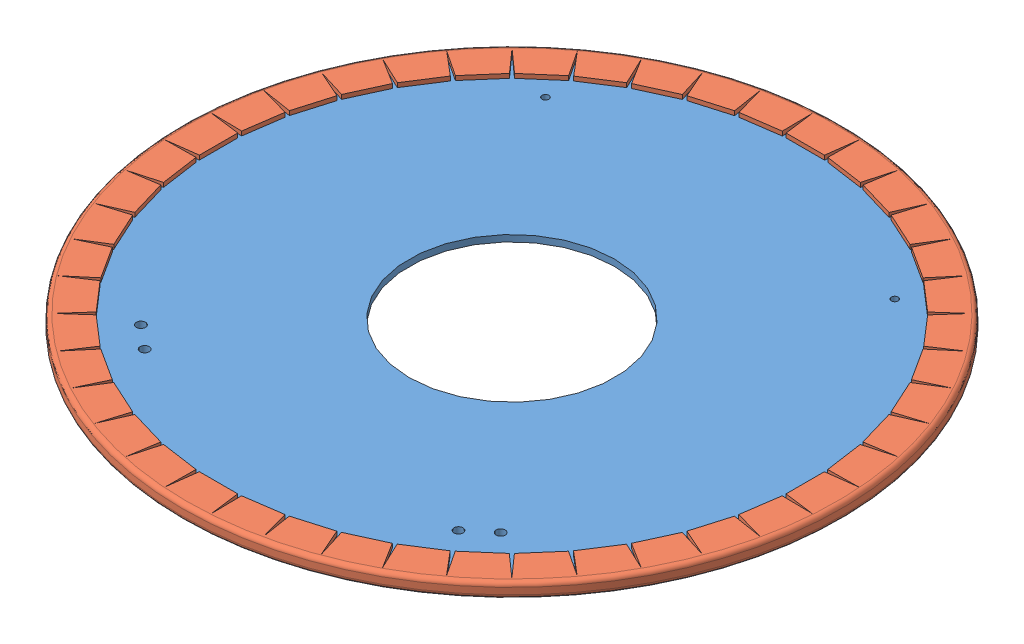
SolidWorks assembly GE-19244, configuration Sourcing. Lengths in mm.
Overall size (488.95 11.11 488.95).
20 component instances, 9 part files, 40 mates.
Components (placement in the parent):
- GE-19245-1: GE-19245 [Default] at origin size (482.6 4.76 482.6)
- GE-19153-1: GE-19153 [Default] at (0 -3.175 0) size (488.95 11.11 488.95)
- GE-19246-1: GE-19246 [1030A11] at (-132.0312 -25.527 157.0523) x (-0.642788 0 0.766044) z (0 1 0) size (50.8 38.1 25.53) (suppressed, hidden)
- GE-19246-2: GE-19246 [1030A11] at (132.0312 -25.527 157.0523) x (0.642788 0 0.766044) z (0 1 0) size (50.8 38.1 25.53) (suppressed, hidden)
- GE-19247-1: GE-19247 [Default] at (-129.594 -7.9375 -154.4441) x (0.732805 0 -0.680438) z (-0.680438 0 -0.732805) size (39.69 20.64 12.7) (suppressed, hidden)
- GE-19247-2: GE-19247 [Default] at (129.594 -7.9375 -154.4441) x (-0.777151 0 -0.629315) z (-0.629315 0 0.777151) size (39.69 20.64 12.7) (suppressed, hidden)
- spacer_.192_.5_.3125-1: spacer_.192_.5_.3125 [94639A551] at (129.594 -3.9688 -154.4441) x (1 0 0) z (0 -1 0) size (12.7 12.7 7.94) (suppressed, hidden)
- spacer_.192_.5_.3125-2: spacer_.192_.5_.3125 [94639A551] at (-129.594 -3.9688 -154.4441) x (1 0 0) z (0 -1 0) size (12.7 12.7 7.94) (suppressed, hidden)
- round_hex_.25_20_.75_full-1: round_hex_.25_20_.75_full [91255A540] at (133.4264 8.1153 141.7234) x (-0.837169 0 -0.546944) z (0 1 0) size (11.1 11.1 22.63) (suppressed, hidden)
- round_hex_.25_20_.75_full-2: round_hex_.25_20_.75_full [91255A540] at (116.4011 8.1153 156.0094) x (-0.925243 0 -0.379375) z (0 1 0) size (11.1 11.1 22.63) (suppressed, hidden)
- round_hex_.25_20_.75_full-4: round_hex_.25_20_.75_full [91255A540] at (-116.4011 8.1153 156.0094) x (-0.985271 0 -0.170998) z (0 1 0) size (11.1 11.1 22.63) (suppressed, hidden)
- round_hex_.25_20_.75_full-6: round_hex_.25_20_.75_full [91255A540] at (-133.4264 8.1153 141.7234) x (-0.997902 0 0.064746) z (0 1 0) size (11.1 11.1 22.63) (suppressed, hidden)
- nylock_.25_20-1: nylock_.25_20 [Default] at (-133.4264 -3.302 141.7234) x (-0.837169 0 -0.546944) z (-0.546944 0 0.837169) size (11.11 7.94 12.83) (suppressed, hidden)
- nylock_.25_20-2: nylock_.25_20 [Default] at (-116.4011 -3.302 156.0094) x (-0.925243 0 -0.379375) z (-0.379375 0 0.925243) size (11.11 7.94 12.83) (suppressed, hidden)
- nylock_.25_20-4: nylock_.25_20 [Default] at (116.4011 -3.302 156.0094) x (-0.985271 0 -0.170998) z (-0.170998 0 0.985271) size (11.11 7.94 12.83) (suppressed, hidden)
- nylock_.25_20-6: nylock_.25_20 [Default] at (133.4264 -3.302 141.7234) x (-0.997902 0 0.064746) z (0.064746 0 0.997902) size (11.11 7.94 12.83) (suppressed, hidden)
- round_hex_10_32_1.5_partial-1: round_hex_10_32_1.5_partial [91255A275] at (-129.594 7.3279 -154.4441) x (-0.837169 0 -0.546944) z (0 1 0) size (9.17 9.17 40.85) (suppressed, hidden)
- round_hex_10_32_1.5_partial-2: round_hex_10_32_1.5_partial [91255A275] at (129.594 7.3279 -154.4441) x (-0.837169 0 -0.546944) z (0 1 0) size (9.17 9.17 40.85) (suppressed, hidden)
- nylock_10_32-1: nylock_10_32 [90631A411] at (129.594 -23.1775 -154.4441) x (-0.837169 0 -0.546944) z (-0.546944 0 0.837169) size (9.53 5.95 11) (suppressed, hidden)
- nylock_10_32-2: nylock_10_32 [90631A411] at (-129.594 -23.1775 -154.4441) x (-0.837169 0 -0.546944) z (-0.546944 0 0.837169) size (9.53 5.95 11) (suppressed, hidden)
Mates (geometry in assembly coordinates):
- Concentric1: concentric: circle of GE-19245-1; circle of GE-19153-1
- Coincident1: coincident: plane of GE-19245-1 through (0 4.7625 0) normal (0 1 0); plane of GE-19153-1 through (0 4.7625 -190.5) normal (0 -1 0)
- Concentric2: concentric: circle of GE-19245-1; circle of GE-19246-1
- Concentric7: concentric: cylinder of GE-19245-1 through (-116.4011 0 156.0094) axis (0 -1 0) radius 3.3782; cylinder of GE-19246-1 through (-116.6929 -25.527 155.7645) axis (0 1 0) radius 3.175
- Coincident2: coincident: plane of GE-19245-1 through (0 0 0) normal (0 -1 0); plane of GE-19246-1 through (-116.1319 0 167.7408) normal (0 1 0)
- Concentric9: concentric: circle of GE-19245-1; circle of GE-19246-2
- Concentric11: concentric: cylinder of GE-19245-1 through (116.4011 0 156.0094) axis (0 -1 0) radius 3.3782; cylinder of GE-19246-2 through (116.6929 -25.527 155.7645) axis (0 1 0) radius 3.175
- Coincident4: coincident: plane of GE-19245-1 through (0 0 0) normal (0 -1 0); plane of GE-19246-2 through (145.3182 0 143.2506) normal (0 1 0)
- Concentric12: concentric: cylinder of GE-19245-1 through (129.594 0 -154.4441) axis (0 -1 0) radius 2.5527; circle of GE-19247-2
- Concentric13: concentric: circle of GE-19245-1; circle of GE-19247-1
- Coincident5: coincident: plane of assembly; plane of assembly; plane of GE-19247-1 through (-129.594 -23.1775 -154.4441) normal (0 -1 0); plane of GE-19247-2 through (129.594 -23.1775 -154.4441) normal (0 -1 0)
- Concentric14: concentric: circle of GE-19245-1; cylinder of spacer_.192_.5_.3125-1 through (129.594 -7.9375 -154.4441) axis (0 1 0) radius 2.4384
- Coincident6: coincident: plane of GE-19245-1 through (0 0 0) normal (0 -1 0); plane of spacer_.192_.5_.3125-1 through (129.594 0 -154.4441) normal (0 1 0)
- Concentric15: concentric: circle of GE-19245-1; cylinder of spacer_.192_.5_.3125-2 through (-129.594 -7.9375 -154.4441) axis (0 1 0) radius 2.4384
- Coincident7: coincident: plane of GE-19245-1 through (0 0 0) normal (0 -1 0); plane of spacer_.192_.5_.3125-2 through (-129.594 0 -154.4441) normal (0 1 0)
- Coincident8: coincident: plane of assembly; plane of assembly; plane of GE-19247-1 through (-129.594 -7.9375 -154.4441) normal (0 1 0); plane of spacer_.192_.5_.3125-2 through (-129.594 -7.9375 -154.4441) normal (0 -1 0)
- Concentric16: concentric: circle of GE-19245-1; cylinder of round_hex_.25_20_.75_full-1 through (133.4264 -14.2875 141.7234) axis (0 -1 0) radius 3.175
- Coincident9: coincident: plane of GE-19245-1 through (0 4.7625 0) normal (0 1 0); plane of round_hex_.25_20_.75_full-1 through (136.4619 4.7625 137.0772) normal (0 -1 0)
- Concentric17: concentric: cylinder of GE-19245-1 through (116.4011 0 156.0094) axis (0 -1 0) radius 3.3782; cylinder of round_hex_.25_20_.75_full-2 through (116.4011 -14.2875 156.0094) axis (0 -1 0) radius 3.175
- Coincident10: coincident: plane of GE-19245-1 through (0 4.7625 0) normal (0 1 0); plane of round_hex_.25_20_.75_full-2 through (118.5066 4.7625 150.8744) normal (0 -1 0)
- Concentric18: concentric: cylinder of GE-19245-1 through (-116.4011 0 156.0094) axis (0 -1 0) radius 3.3782; cylinder of round_hex_.25_20_.75_full-4 through (-116.4011 -14.2875 156.0094) axis (0 -1 0) radius 3.175
- Coincident11: coincident: plane of GE-19245-1 through (0 4.7625 0) normal (0 1 0); plane of round_hex_.25_20_.75_full-4 through (-115.4521 4.7625 150.5412) normal (0 -1 0)
- Concentric19: concentric: cylinder of GE-19245-1 through (-133.4264 0 141.7234) axis (0 -1 0) radius 3.3782; cylinder of round_hex_.25_20_.75_full-6 through (-133.4264 -14.2875 141.7234) axis (0 -1 0) radius 3.175
- Coincident12: coincident: plane of GE-19245-1 through (0 4.7625 0) normal (0 1 0); plane of round_hex_.25_20_.75_full-6 through (-133.7858 4.7625 136.1852) normal (0 -1 0)
- Concentric20: concentric: cylinder of assembly; cylinder of assembly; cylinder of round_hex_.25_20_.75_full-6 through (-133.4264 -14.2875 141.7234) axis (0 -1 0) radius 3.175; cylinder of nylock_.25_20-1 through (-133.4264 -3.302 141.7234) axis (0 -1 0) radius 3.175
- Coincident13: coincident: plane of assembly; plane of assembly; plane of GE-19246-1 through (-116.1319 -3.302 167.7408) normal (0 -1 0); plane of nylock_.25_20-1 through (-133.4264 -3.302 141.7234) normal (0 1 0)
- Concentric21: concentric: cylinder of assembly; cylinder of assembly; cylinder of round_hex_.25_20_.75_full-4 through (-116.4011 -14.2875 156.0094) axis (0 -1 0) radius 3.175; cylinder of nylock_.25_20-2 through (-116.4011 -3.302 156.0094) axis (0 -1 0) radius 3.175
- Coincident14: coincident: plane of assembly; plane of assembly; plane of GE-19246-1 through (-116.1319 -3.302 167.7408) normal (0 -1 0); plane of nylock_.25_20-2 through (-116.4011 -3.302 156.0094) normal (0 1 0)
- Concentric22: concentric: cylinder of assembly; cylinder of assembly; cylinder of round_hex_.25_20_.75_full-2 through (116.4011 -14.2875 156.0094) axis (0 -1 0) radius 3.175; cylinder of nylock_.25_20-4 through (116.4011 -3.302 156.0094) axis (0 -1 0) radius 3.175
- Coincident15: coincident: plane of assembly; plane of assembly; plane of GE-19246-2 through (145.3182 -3.302 143.2506) normal (0 -1 0); plane of nylock_.25_20-4 through (116.4011 -3.302 156.0094) normal (0 1 0)
- Concentric23: concentric: cylinder of assembly; cylinder of assembly; cylinder of round_hex_.25_20_.75_full-1 through (133.4264 -14.2875 141.7234) axis (0 -1 0) radius 3.175; cylinder of nylock_.25_20-6 through (133.4264 -3.302 141.7234) axis (0 -1 0) radius 3.175
- Coincident16: coincident: plane of assembly; plane of assembly; plane of GE-19246-2 through (145.3182 -3.302 143.2506) normal (0 -1 0); plane of nylock_.25_20-6 through (133.4264 -3.302 141.7234) normal (0 1 0)
- Concentric24: concentric: cylinder of GE-19245-1 through (-129.594 0 -154.4441) axis (0 -1 0) radius 2.5527; cylinder of round_hex_10_32_1.5_partial-1 through (-129.594 -33.3375 -154.4441) axis (0 -1 0) radius 2.413
- Coincident17: coincident: plane of GE-19245-1 through (0 4.7625 0) normal (0 1 0); plane of round_hex_10_32_1.5_partial-1 through (-127.0864 4.7625 -158.2823) normal (0 -1 0)
- Concentric25: concentric: cylinder of GE-19245-1 through (129.594 0 -154.4441) axis (0 -1 0) radius 2.5527; cylinder of round_hex_10_32_1.5_partial-2 through (129.594 -33.3375 -154.4441) axis (0 -1 0) radius 2.413
- Coincident18: coincident: plane of GE-19245-1 through (0 4.7625 0) normal (0 1 0); plane of round_hex_10_32_1.5_partial-2 through (132.1016 4.7625 -158.2823) normal (0 -1 0)
- Concentric26: concentric: cylinder of assembly; cylinder of assembly; cylinder of round_hex_10_32_1.5_partial-1 through (-129.594 -33.3375 -154.4441) axis (0 -1 0) radius 2.413; cylinder of nylock_10_32-2 through (-129.594 -20.7645 -154.4441) axis (0 1 0) radius 2.413
- Coincident19: coincident: plane of assembly; plane of assembly; plane of GE-19247-1 through (-129.594 -23.1775 -154.4441) normal (0 -1 0); plane of nylock_10_32-2 through (-126.5862 -23.1775 -159.0479) normal (0 1 0)
- Concentric27: concentric: cylinder of assembly; cylinder of assembly; cylinder of round_hex_10_32_1.5_partial-2 through (129.594 -33.3375 -154.4441) axis (0 -1 0) radius 2.413; cylinder of nylock_10_32-1 through (129.594 -20.7645 -154.4441) axis (0 1 0) radius 2.413
- Coincident20: coincident: plane of assembly; plane of assembly; plane of GE-19247-2 through (129.594 -23.1775 -154.4441) normal (0 -1 0); plane of nylock_10_32-1 through (132.6018 -23.1775 -159.0479) normal (0 1 0)
